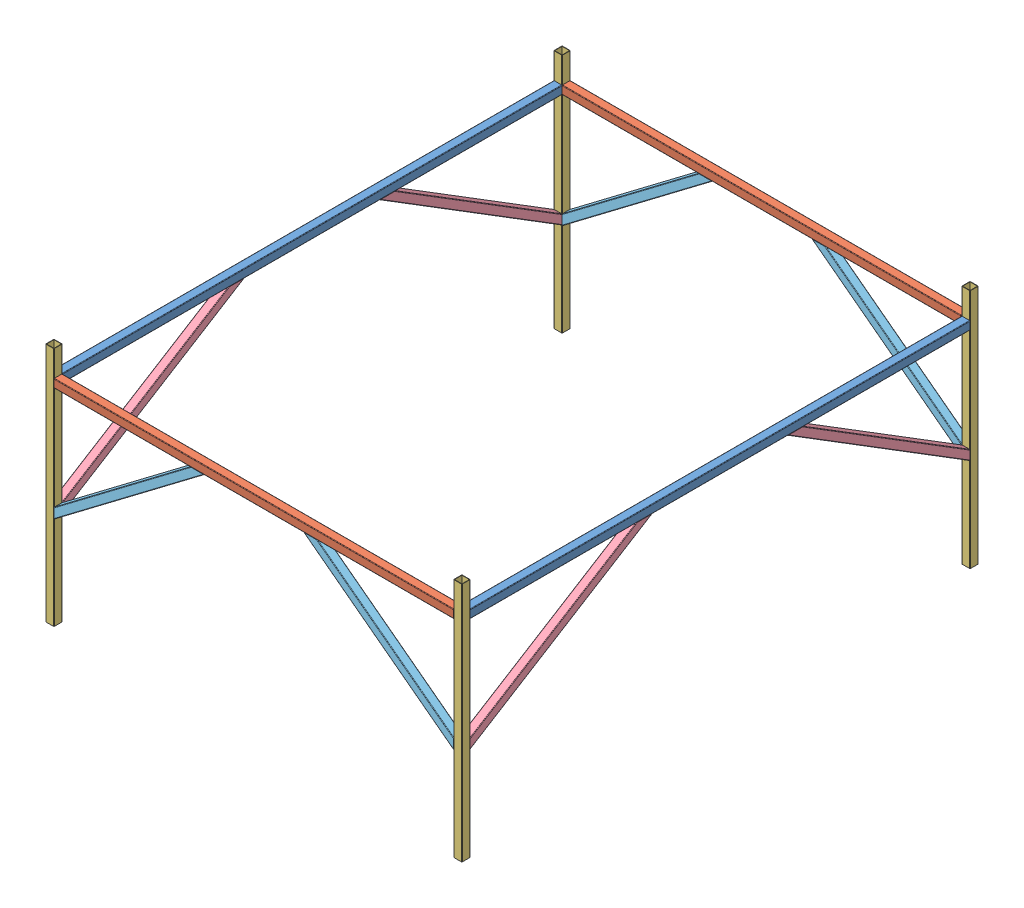
SolidWorks assembly Table_Assembly, configuration Default. Lengths in mm.
Overall size (1612 932 2000).
16 component instances, 5 part files, 44 mates.
Components (placement in the parent):
- 1.936m_Square_Tubing_32mm-1: 1.936m_Square_Tubing_32mm [Default] at (694.6533 1003.5042 1505.447) size (32 32 1936)
- 1.548m_Square_Tubing_32mm-1: 1.548m_Square_Tubing_32mm [Default] at (-95.3467 1003.5042 2489.447) x (0 0 -1) z (1 0 0) size (32 32 1548)
- 932mm_Square_Tubing_32mm-1: 932mm_Square_Tubing_32mm [Default] at (694.6533 653.5042 2489.447) x (0 0 1) z (0 -1 0) size (32 32 932)
- 1.936m_Square_Tubing_32mm-2: 1.936m_Square_Tubing_32mm [Default] at (-885.3467 1003.5042 1505.447) size (32 32 1936)
- 1.548m_Square_Tubing_32mm-2: 1.548m_Square_Tubing_32mm [Default] at (-95.3467 1003.5042 521.447) x (0 0 1) z (-1 0 0) size (32 32 1548)
- 932mm_Square_Tubing_32mm-2: 932mm_Square_Tubing_32mm [Default] at (-885.3467 653.5042 2489.447) x (0 0 1) z (0 -1 0) size (32 32 932)
- 932mm_Square_Tubing_32mm-3: 932mm_Square_Tubing_32mm [Default] at (-885.3467 653.5042 521.447) x (0 0 1) z (0 -1 0) size (32 32 932)
- 932mm_Square_Tubing_32mm-4: 932mm_Square_Tubing_32mm [Default] at (694.6533 653.5042 521.447) x (0 0 1) z (0 -1 0) size (32 32 932)
- 760.5mm_Square_Tubing_32mm-1: 760.5mm_Square_Tubing_32mm [Default] at (694.6533 782.2473 2129.0435) x (-1 0 0) z (0 0.527104 -0.849801) size (32 32 830.4)
- 760.5mm_Square_Tubing_32mm-2: 760.5mm_Square_Tubing_32mm [Default] at (-885.3467 782.2473 2129.0435) x (-1 0 0) z (0 0.527104 -0.849801) size (32 32 830.4)
- 760.5mm_Square_Tubing_32mm-3: 760.5mm_Square_Tubing_32mm [Default] at (-885.3467 782.2473 881.8506) x (1 0 0) z (0 0.527104 0.849801) size (32 32 830.4)
- 760.5mm_Square_Tubing_32mm-4: 760.5mm_Square_Tubing_32mm [Default] at (694.6533 782.2473 881.8506) x (1 0 0) z (0 0.527104 0.849801) size (32 32 830.4)
- 662.5mm_Square_Tubing_32mm-1: 662.5mm_Square_Tubing_32mm [Default] at (-588.3599 780.2914 2489.447) x (0 0 -1) z (0.797373 0.603486 0) size (32 32 729)
- 662.5mm_Square_Tubing_32mm-2: 662.5mm_Square_Tubing_32mm [Default] at (397.6665 780.2914 2489.447) x (0 0 1) z (-0.797373 0.603486 0) size (32 32 729)
- 662.5mm_Square_Tubing_32mm-3: 662.5mm_Square_Tubing_32mm [Default] at (397.6665 780.2914 521.447) x (0 0 1) z (-0.797373 0.603486 0) size (32 32 729)
- 662.5mm_Square_Tubing_32mm-4: 662.5mm_Square_Tubing_32mm [Default] at (-588.3599 780.2914 521.447) x (0 0 -1) z (0.797373 0.603486 0) size (32 32 729)
Mates (geometry in assembly coordinates):
- Coincident1: coincident anti-aligned: plane of 1.936m_Square_Tubing_32mm-1 through (678.6533 989.5042 537.447) normal (-1 0 0); plane of 1.548m_Square_Tubing_32mm-1 through (678.6533 989.5042 2475.447) normal (1 0 0)
- Coincident2: coincident aligned: plane of 1.936m_Square_Tubing_32mm-1 through (680.6533 1019.5042 537.447) normal (0 1 0); plane of 1.548m_Square_Tubing_32mm-1 through (-869.3467 1019.5042 2503.447) normal (0 1 0)
- Coincident5: coincident aligned: line of 1.548m_Square_Tubing_32mm-1 through (-869.3467 989.5042 2473.447) axis (0 1 0); line of 1.936m_Square_Tubing_32mm-2 through (-869.3467 989.5042 2473.447) axis (0 1 0)
- Coincident6: coincident aligned: plane of 1.548m_Square_Tubing_32mm-1 through (-869.3467 1019.5042 2503.447) normal (0 1 0); plane of 1.936m_Square_Tubing_32mm-2 through (-899.3467 1019.5042 537.447) normal (0 1 0)
- Coincident7: coincident anti-aligned: line of 1.936m_Square_Tubing_32mm-1 through (678.6533 1017.5042 2473.447) axis (0 -1 0); line of 1.548m_Square_Tubing_32mm-1 through (678.6533 989.5042 2473.447) axis (0 1 0)
- Coincident8: coincident anti-aligned: plane of 1.548m_Square_Tubing_32mm-1 through (678.6533 989.5042 2475.447) normal (1 0 0); plane of 932mm_Square_Tubing_32mm-1 through (678.6533 1119.5042 2475.447) normal (-1 0 0)
- Coincident9: coincident anti-aligned: plane of 1.936m_Square_Tubing_32mm-1 through (708.6533 989.5042 2473.447) normal (0 0 1); plane of 932mm_Square_Tubing_32mm-1 through (708.6533 1119.5042 2473.447) normal (0 0 -1)
- Coincident10: coincident: line of 932mm_Square_Tubing_32mm-1 through (710.6533 1119.5042 2475.447) axis (0 0 1)
- Coincident11: coincident anti-aligned: plane of 1.936m_Square_Tubing_32mm-2 through (-871.3467 989.5042 2473.447) normal (0 0 1); plane of 932mm_Square_Tubing_32mm-2 through (-871.3467 1119.5042 2473.447) normal (0 0 -1)
- Coincident12: coincident anti-aligned: plane of 1.548m_Square_Tubing_32mm-1 through (-869.3467 989.5042 2475.447) normal (-1 0 0); plane of 932mm_Square_Tubing_32mm-2 through (-869.3467 1119.5042 2475.447) normal (1 0 0)
- Coincident13: coincident aligned: plane of 932mm_Square_Tubing_32mm-1 through (708.6533 1119.5042 2503.447) normal (0 1 0); plane of 932mm_Square_Tubing_32mm-2 through (-871.3467 1119.5042 2503.447) normal (0 1 0)
- Coincident14: coincident anti-aligned: plane of 1.936m_Square_Tubing_32mm-2 through (-871.3467 989.5042 537.447) normal (0 0 -1); plane of 932mm_Square_Tubing_32mm-3 through (-871.3467 1119.5042 537.447) normal (0 0 1)
- Coincident15: coincident aligned: plane of 1.936m_Square_Tubing_32mm-2 through (-901.3467 989.5042 537.447) normal (-1 0 0); plane of 932mm_Square_Tubing_32mm-3 through (-901.3467 1119.5042 507.447) normal (-1 0 0)
- Coincident16: coincident aligned: plane of 932mm_Square_Tubing_32mm-2 through (-871.3467 1119.5042 2503.447) normal (0 1 0); plane of 932mm_Square_Tubing_32mm-3 through (-871.3467 1119.5042 535.447) normal (0 1 0)
- Coincident17: coincident aligned: plane of 932mm_Square_Tubing_32mm-1 through (708.6533 1119.5042 2503.447) normal (0 1 0); plane of 932mm_Square_Tubing_32mm-4 through (708.6533 1119.5042 535.447) normal (0 1 0)
- Coincident18: coincident anti-aligned: plane of 1.936m_Square_Tubing_32mm-1 through (708.6533 989.5042 537.447) normal (0 0 -1); plane of 932mm_Square_Tubing_32mm-4 through (708.6533 1119.5042 537.447) normal (0 0 1)
- Coincident19: coincident aligned: plane of 1.936m_Square_Tubing_32mm-1 through (710.6533 989.5042 537.447) normal (1 0 0); plane of 932mm_Square_Tubing_32mm-4 through (710.6533 1119.5042 507.447) normal (1 0 0)
- Coincident20: coincident anti-aligned: plane of 1.548m_Square_Tubing_32mm-2 through (678.6533 989.5042 535.447) normal (1 0 0); plane of 932mm_Square_Tubing_32mm-4 through (678.6533 1119.5042 507.447) normal (-1 0 0)
- Coincident21: coincident aligned: plane of 1.548m_Square_Tubing_32mm-2 through (678.6533 989.5042 505.447) normal (0 0 -1); plane of 932mm_Square_Tubing_32mm-4 through (708.6533 1119.5042 505.447) normal (0 0 -1)
- Coincident22: coincident aligned: plane of 1.936m_Square_Tubing_32mm-1 through (680.6533 1019.5042 537.447) normal (0 1 0); plane of 1.548m_Square_Tubing_32mm-2 through (678.6533 1019.5042 507.447) normal (0 1 0)
- Coincident26: coincident anti-aligned: plane of 1.936m_Square_Tubing_32mm-1 through (680.6533 987.5042 537.447) normal (0 -1 0); plane of 760.5mm_Square_Tubing_32mm-1 through (710.6533 987.5042 1767.7725) normal (0 1 0)
- Coincident27: coincident anti-aligned: plane of 932mm_Square_Tubing_32mm-1 through (708.6533 1119.5042 2473.447) normal (0 0 -1); plane of 760.5mm_Square_Tubing_32mm-1 through (710.6533 549.7969 2473.447) normal (0 0 1)
- Coincident28: coincident aligned: plane of 1.936m_Square_Tubing_32mm-1 through (710.6533 989.5042 537.447) normal (1 0 0); plane of 760.5mm_Square_Tubing_32mm-1 through (710.6533 551.4965 2474.5012) normal (1 0 0)
- Coincident29: coincident anti-aligned: plane of 1.936m_Square_Tubing_32mm-1 through (680.6533 987.5042 537.447) normal (0 -1 0); plane of 760.5mm_Square_Tubing_32mm-4 through (678.6533 987.5042 1243.1215) normal (0 1 0)
- Coincident30: coincident aligned: plane of 1.936m_Square_Tubing_32mm-1 through (710.6533 989.5042 537.447) normal (1 0 0); plane of 760.5mm_Square_Tubing_32mm-4 through (710.6533 551.4965 536.3928) normal (1 0 0)
- Coincident31: coincident anti-aligned: plane of 932mm_Square_Tubing_32mm-4 through (708.6533 1119.5042 537.447) normal (0 0 1); plane of 760.5mm_Square_Tubing_32mm-4 through (678.6533 549.7969 537.447) normal (0 0 -1)
- Coincident32: coincident anti-aligned: plane of 1.936m_Square_Tubing_32mm-2 through (-899.3467 987.5042 537.447) normal (0 -1 0); plane of 760.5mm_Square_Tubing_32mm-3 through (-901.3467 987.5042 1243.1215) normal (0 1 0)
- Coincident33: coincident aligned: plane of 1.936m_Square_Tubing_32mm-2 through (-901.3467 989.5042 537.447) normal (-1 0 0); plane of 760.5mm_Square_Tubing_32mm-3 through (-901.3467 551.4965 536.3928) normal (-1 0 0)
- Coincident34: coincident anti-aligned: plane of 932mm_Square_Tubing_32mm-3 through (-871.3467 1119.5042 537.447) normal (0 0 1); plane of 760.5mm_Square_Tubing_32mm-3 through (-901.3467 549.7969 537.447) normal (0 0 -1)
- Coincident35: coincident anti-aligned: plane of 1.936m_Square_Tubing_32mm-2 through (-899.3467 987.5042 537.447) normal (0 -1 0); plane of 760.5mm_Square_Tubing_32mm-2 through (-869.3467 987.5042 1767.7725) normal (0 1 0)
- Coincident36: coincident anti-aligned: plane of 932mm_Square_Tubing_32mm-2 through (-871.3467 1119.5042 2473.447) normal (0 0 -1); plane of 760.5mm_Square_Tubing_32mm-2 through (-869.3467 549.7969 2473.447) normal (0 0 1)
- Coincident37: coincident aligned: plane of 1.936m_Square_Tubing_32mm-2 through (-901.3467 989.5042 537.447) normal (-1 0 0); plane of 760.5mm_Square_Tubing_32mm-2 through (-901.3467 551.4965 2474.5012) normal (-1 0 0)
- Coincident38: coincident anti-aligned: plane of 1.548m_Square_Tubing_32mm-1 through (-869.3467 987.5042 2503.447) normal (0 -1 0); plane of 662.5mm_Square_Tubing_32mm-1 through (-288.0616 987.5042 2505.447) normal (0 1 0)
- Coincident39: coincident anti-aligned: plane of 932mm_Square_Tubing_32mm-2 through (-869.3467 1119.5042 2475.447) normal (1 0 0); plane of 662.5mm_Square_Tubing_32mm-1 through (-869.3467 547.5626 2505.447) normal (-1 0 0)
- Coincident40: coincident aligned: plane of 932mm_Square_Tubing_32mm-2 through (-871.3467 1119.5042 2505.447) normal (0 0 1); plane of 662.5mm_Square_Tubing_32mm-1 through (-870.5537 549.1574 2505.447) normal (0 0 1)
- Coincident41: coincident anti-aligned: plane of 1.548m_Square_Tubing_32mm-1 through (-869.3467 987.5042 2503.447) normal (0 -1 0); plane of 662.5mm_Square_Tubing_32mm-2 through (97.3681 987.5042 2473.447) normal (0 1 0)
- Coincident42: coincident anti-aligned: plane of 662.5mm_Square_Tubing_32mm-2 through (678.6533 547.5626 2473.447) normal (1 0 0); plane of 932mm_Square_Tubing_32mm-1 through (678.6533 1119.5042 2475.447) normal (-1 0 0)
- Coincident43: coincident aligned: plane of 932mm_Square_Tubing_32mm-1 through (708.6533 1119.5042 2505.447) normal (0 0 1); plane of 662.5mm_Square_Tubing_32mm-2 through (679.8602 549.1574 2505.447) normal (0 0 1)
- Coincident44: coincident anti-aligned: plane of 1.548m_Square_Tubing_32mm-2 through (678.6533 987.5042 507.447) normal (0 -1 0); plane of 662.5mm_Square_Tubing_32mm-4 through (-288.0616 987.5042 537.447) normal (0 1 0)
- Coincident45: coincident anti-aligned: plane of 932mm_Square_Tubing_32mm-3 through (-869.3467 1119.5042 507.447) normal (1 0 0); plane of 662.5mm_Square_Tubing_32mm-4 through (-869.3467 547.5626 537.447) normal (-1 0 0)
- Coincident46: coincident aligned: plane of 1.548m_Square_Tubing_32mm-2 through (678.6533 989.5042 505.447) normal (0 0 -1); plane of 662.5mm_Square_Tubing_32mm-4 through (-870.5537 549.1574 505.447) normal (0 0 -1)
- Coincident47: coincident anti-aligned: plane of 932mm_Square_Tubing_32mm-4 through (678.6533 1119.5042 507.447) normal (-1 0 0); plane of 662.5mm_Square_Tubing_32mm-3 through (678.6533 547.5626 505.447) normal (1 0 0)
- Coincident48: coincident anti-aligned: plane of 1.548m_Square_Tubing_32mm-2 through (678.6533 987.5042 507.447) normal (0 -1 0); plane of 662.5mm_Square_Tubing_32mm-3 through (97.3681 987.5042 505.447) normal (0 1 0)
- Coincident49: coincident aligned: plane of 1.548m_Square_Tubing_32mm-2 through (678.6533 989.5042 505.447) normal (0 0 -1); plane of 662.5mm_Square_Tubing_32mm-3 through (679.8602 549.1574 505.447) normal (0 0 -1)
